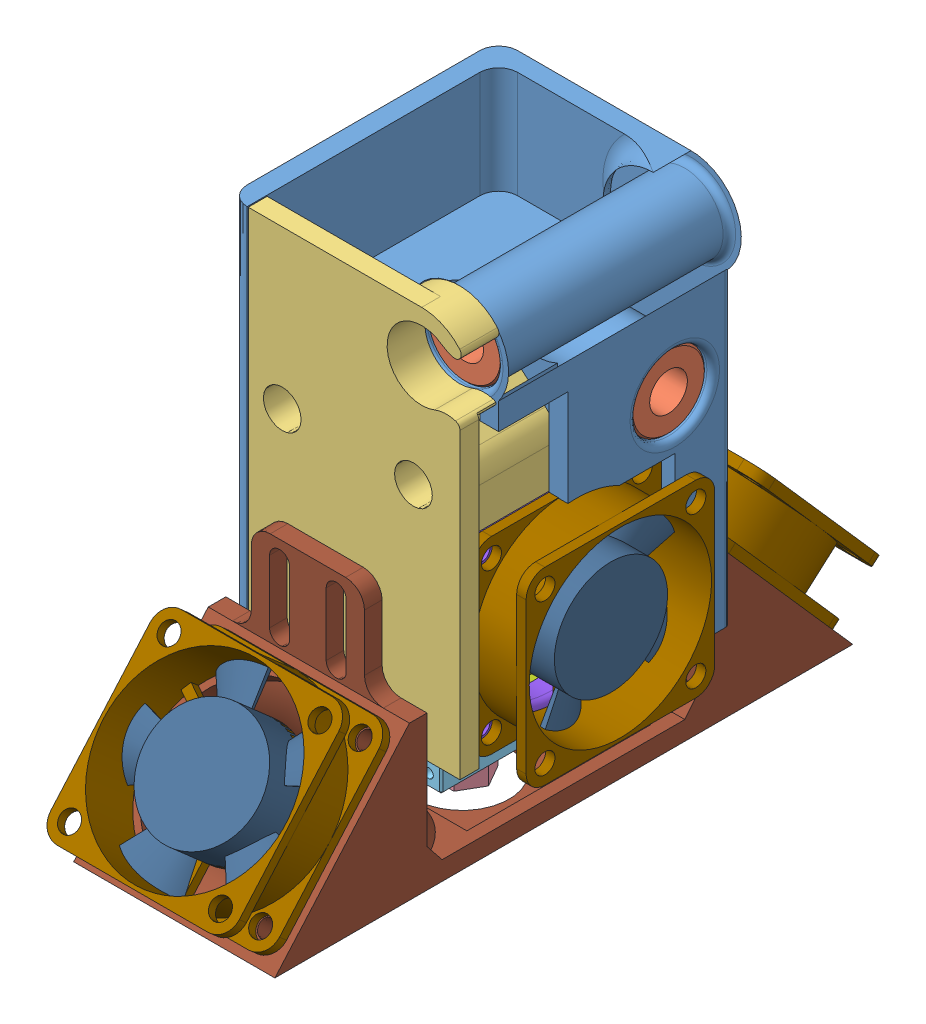
SolidWorks assembly HeadHolder, configuration По умолчанию. Lengths in mm.
Overall size (47.76 86.12 111.31).
21 component instances, 11 part files, 19 mates.
Components (placement in the parent):
- e3d mount-1: e3d mount [По умолчанию] at (25.1783 50.5308 52.2407) size (38.58 65 43)
- 1065-Z1P-A-1: 1065-Z1P-A [По умолчанию] at (36.7533 59.5308 46.0907) size (12 12 35)
- 1065-Z1P-A-2: 1065-Z1P-A [По умолчанию] at (24.6783 41.5308 36.5907) x (0 0 -1) z (1 0 0) size (12 12 35)
- e3d clamp-1: e3d clamp [По умолчанию] at (44.199 34.072 69.7407) x (-1 0 0) z (0 0 -1) size (33.87 62.02 18.57)
- e3d v6-1: e3d v6 [Default] at (25.1783 -7.1592 52.2407) size (40.5 61.3 39.45)
  - e3d nozzle (0.4)-1: e3d nozzle (0.4) [Default] at (0 -4.25 0) size (8.08 12.5 7)
  - e3d heaterblock-2: e3d heaterblock [Default] at (-5.5 -1.25 0) size (20 11.5 16)
  - e3d heat break-2: e3d heat break [Default] at (0 5.25 0) size (7 21.9 7)
  - e3d heatsink-2: e3d heatsink [Default] at (0 12.35 0) x (0.978214 0 -0.207597) z (0.207597 0 0.978214) size (22.3 42.7 22.3)
  - fanduct-2: fanduct [Default] at (6.8279 9.7284 26.4875) x (-1 0 0) z (0 0 -1) size (32 39.46 39.45)
    - fan duct-1: fan duct [Default] at (6.8279 2.6216 26.4875) size (22.41 30.18 30)
    - fan-1: fan [Default] at (15.7816 1.6787 26.8895) x (0 0 1) z (-1 0 0) size (39.45 39.46 10)
      - fan sub1-1: fan sub1 [Default] at (-0.402 15.9429 23.9537) size (30 30 10)
      - fan sub2-1: fan sub2 [Default] at (-0.402 15.9429 33.9537) x (0 0 1) z (-0.65899 0.752151 0) size (8.5 27.91 28)
- e3d fan-1: e3d fan [По умолчанию] at (0.3031 -31.6908 75.3151) x (0 0 1) z (0 1 0) size (91.9 32 43.08)
- fan-1: fan [Default] at (22.5803 -27.4015 76.917) x (1 0 0) z (0 0.659377 0.751813) size (39.45 39.46 10)
  - fan sub1-1: fan sub1 [Default] at (-0.402 15.9429 23.9537) size (30 30 10)
  - fan sub2-1: fan sub2 [Default] at (-0.402 15.9429 33.9537) x (0 0 1) z (-0.65899 0.752151 0) size (8.5 27.91 28)
- fan-2: fan [Default] at (21.7762 -27.3942 21.5723) x (-1 0 0) z (0 0.661113 -0.750286) size (39.45 39.46 10)
  - fan sub1-1: fan sub1 [Default] at (-0.402 15.9429 23.9537) size (30 30 10)
  - fan sub2-1: fan sub2 [Default] at (-0.402 15.9429 33.9537) x (0 0 1) z (-0.65899 0.752151 0) size (8.5 27.91 28)
Mates (geometry in assembly coordinates):
- Концентричный1: concentric anti-aligned: cylinder of e3d mount-1 through (36.7533 59.5308 27.5907) axis (0 0 1) radius 6.1; cylinder of 1065-Z1P-A-1 through (36.7533 59.5308 63.5907) axis (0 0 -1) radius 6
- Совпадение1: coincident anti-aligned: circle of e3d mount-1; plane of 1065-Z1P-A-1 through (36.7533 59.5308 63.5907) normal (0 0 1)
- Концентричный2: concentric anti-aligned: cylinder of e3d mount-1 through (6.1783 41.5308 36.5907) axis (1 0 0) radius 6.1; cylinder of 1065-Z1P-A-2 through (42.1783 41.5308 36.5907) axis (-1 0 0) radius 6
- Совпадение2: coincident anti-aligned: circle of e3d mount-1; plane of 1065-Z1P-A-2 through (42.1783 41.5308 36.5907) normal (1 0 0)
- Концентричный3: concentric anti-aligned: cylinder of e3d mount-1 through (25.1783 44.1908 52.2407) axis (0 1 0) radius 8.15; cylinder of e3d v6-1/e3d heatsink-2 through (25.1783 47.8908 52.2407) axis (0 -1 0) radius 4
- Совпадение4: coincident anti-aligned: plane of e3d mount-1 through (25.1783 44.1908 52.2407) normal (0 1 0); plane of e3d v6-1/e3d heatsink-2 through (31.0475 44.1908 50.9952) normal (0 -1 0)
- Концентричный4: concentric aligned: cylinder of e3d mount-1 through (14.7483 42.4708 44.2407) axis (0 0 1) radius 1.4; circle of e3d clamp-1
- Совпадение6: coincident anti-aligned: plane of e3d mount-1 through (25.1783 44.1908 52.2407) normal (0 0 1); plane of e3d clamp-1 through (44.199 34.072 52.2407) normal (0 0 -1)
- Совпадение7: coincident aligned: plane of e3d mount-1 through (25.1783 50.5308 52.2407) normal (0 1 0); plane of e3d clamp-1 through (44.199 50.5305 60.2407) normal (0 1 0)
- Параллельность1: parallel aligned: plane of e3d v6-1/e3d heatsink-2 through (28.602 5.1908 51.5142) normal (0 -1 0); plane of e3d fan-1 through (32.835 -11.9092 75.3151) normal (0 -1 0)
- Совпадение9: coincident anti-aligned: plane of e3d mount-1 through (25.1783 50.5308 27.5907) normal (0 0 -1); plane of e3d fan-1 through (32.835 -10.9092 27.5907) normal (0 0 1)
- Совпадение10: coincident aligned: plane of e3d mount-1 through (6.1783 67.5308 64.5907) normal (-1 0 0); plane of e3d fan-1 through (6.1783 -11.9092 70.7907) normal (-1 0 0)
- Совпадение11: coincident anti-aligned: plane of e3d fan-1 through (38.1783 -1.4911 86.0535) normal (0 0.659377 0.751813); plane of fan-1/fan sub1-1 through (22.1783 0.3791 84.4133) normal (0 -0.659377 -0.751813)
- Концентричный9: concentric aligned: circle of e3d fan-1; cylinder of fan-1/fan sub1-1 through (34.1783 10.3899 77.6285) axis (0 0.659377 0.751813) radius 1.6
- Параллельность2: parallel aligned: plane of e3d fan-1 through (38.1783 -11.9092 70.7907) normal (1 0 0); plane of fan-1/fan sub1-1 through (37.1783 -10.8981 94.3039) normal (1 0 0)
- Совпадение14: coincident anti-aligned: plane of e3d fan-1 through (38.1783 24.3795 35.2665) normal (0 0.661113 -0.750286); plane of fan-2/fan sub1-1 through (22.1783 0.4037 14.1402) normal (0 -0.661113 0.750286)
- Концентричный12: concentric aligned: circle of e3d fan-1; circle of fan-2/fan sub1-1
- Параллельность3: parallel aligned: plane of e3d fan-1 through (38.1783 -11.9092 70.7907) normal (1 0 0); plane of fan-2/fan sub1-1 through (37.1783 44.0669 -17.2613) normal (1 0 0)
- Расстояние1: distance = 3 mm anti-aligned: plane of e3d fan-1 through (32.835 -11.4092 75.3151) normal (0 1 0); plane of e3d v6-1/e3d heaterblock-2 through (19.6783 -8.4092 52.2407) normal (0 -1 0)
